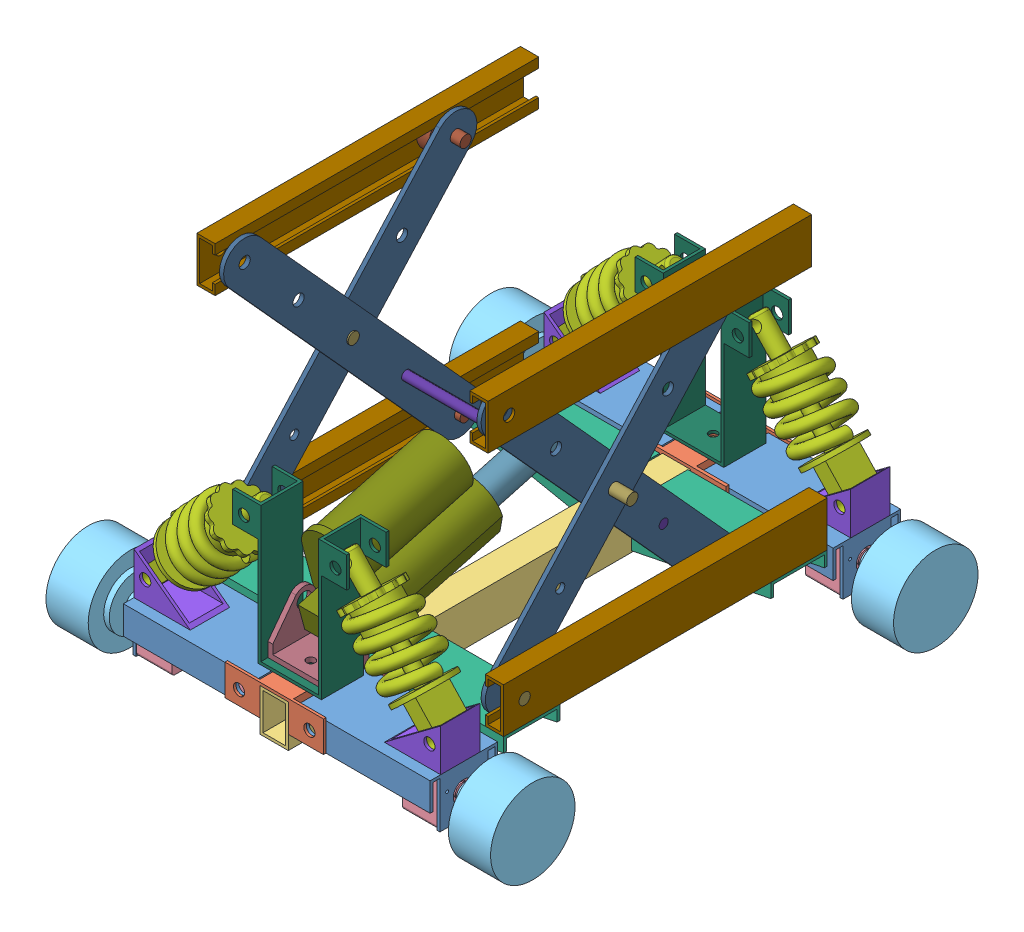
SolidWorks assembly 整体, configuration 默认. Lengths in mm.
Overall size (316 267.94 370.98).
48 component instances, 17 part files, 55 mates.
Components (placement in the parent):
- 电机安装板-1: 电机安装板 [默认] at (86.7266 -11.8451 70) size (94 35 48)
- 电机转动副-1: 电机转动副 [默认] at (82.9126 -31.7003 67.7925) size (70 22 52)
- 矩管-1: 矩管 [默认] at (70.1397 -10.4653 43.5249) x (0 0 -1) z (0 1 0) size (338 20 30)
- 电机和减速器-1: 电机和减速器 [默认] at (33.1161 1.0347 94) x (0 0 1) z (-1 0 0) size (33 33 95)
- 轮子加法兰-1: 轮子加法兰 [默认] at (-93.8839 -6.7848 84.7644) x (0 0.763194 -0.646169) z (1 0 0) size (60 60 47)
- 升降支撑板-1: 升降支撑板 [默认] at (17.4717 0.0393 25.7925) size (99 30 40)
- 减震器10cm中心距-1: 减震器10cm中心距 [默认] at (-6.3734 50.215 84.5) x (0.68369 0.729773 0) z (0 0 1) size (112 51.88 51.88)
- 减震器安装支架-1: 减震器安装支架 [默认] at (-18.6767 23.9575 82.5) size (40 30 28)
- 导轨-1: 导轨 [默认] at (-3.9885 11.2083 65.7925) x (-1 0 0) z (0 0 -1) size (13 32 230)
- 升降剪叉机构-1: 升降剪叉机构 [默认] at (-28.8839 73.8835 -86.4616) x (0 0.741103 0.671391) z (1 0 0) size (258 30 3)
- 轴承带丝杆-1: 轴承带丝杆 [默认] at (-42.8839 24.4917 -97.4559) x (0 -0.806832 -0.590781) z (1 0 0) size (28 28 21)
- 升降剪叉机构-3: 升降剪叉机构 [默认] at (-31.8839 55.9585 15.1833) x (0 0.741103 -0.671391) z (1 0 0) size (258 30 3)
- 轴承带丝杆-2: 轴承带丝杆 [默认] at (-42.8839 195.9799 -111.0939) x (0 0.187759 -0.982215) z (1 0 0) size (28 28 21)
- 减震器10cm中心距-2: 减震器10cm中心距 [默认] at (134.6055 50.215 108.5) x (-0.68369 0.729773 0) z (0 0 -1) size (112 51.88 51.88)
- 电机安装板-2: 电机安装板 [默认] at (41.5056 -11.8451 118) x (-1 0 0) z (0 0 -1) size (94 35 48)
- 减震器安装支架-2: 减震器安装支架 [默认] at (146.9089 23.9575 110.5) x (-1 0 0) z (0 0 -1) size (40 30 28)
- 轮子加法兰-2: 轮子加法兰 [默认] at (222.1161 -6.7848 84.7644) x (0 -0.763194 0.646169) z (-1 0 0) size (60 60 47)
- 电机和减速器-2: 电机和减速器 [默认] at (95.1161 1.0347 94) x (0 0 -1) z (1 0 0) size (33 33 95)
- 升降支撑板-2: 升降支撑板 [默认] at (110.7605 0.0393 65.7925) x (-1 0 0) z (0 0 -1) size (99 30 40)
- 升降剪叉机构-6: 升降剪叉机构 [默认] at (157.1161 55.9585 -66.6755) x (0 0.741103 0.671391) z (-1 0 0) size (258 30 3)
- 升降剪叉机构-7: 升降剪叉机构 [默认] at (160.1161 73.8835 34.9694) x (0 0.741103 -0.671391) z (-1 0 0) size (258 30 3)
- 轴承带丝杆-5: 轴承带丝杆 [默认] at (171.1161 35.5677 -89.3458) x (0 0.806832 0.590781) z (-1 0 0) size (28 28 21)
- 导轨-7: 导轨 [默认] at (132.2207 61.8611 65.7925) x (1 0 0) z (0 0 -1) size (13 32 230)
- 导轨-8: 导轨 [默认] at (-3.9885 180.1798 65.7925) x (-1 0 0) z (0 0 -1) size (13 32 230)
- 轮子加法兰-3: 轮子加法兰 [默认] at (-93.8839 -6.7848 -183.1793) x (0 -0.763194 -0.646169) z (1 0 0) size (60 60 47)
- 减震器10cm中心距-3: 减震器10cm中心距 [默认] at (-6.3734 50.215 -206.9149) x (0.68369 0.729773 0) z (0 0 1) size (112 51.88 51.88)
- 电机安装板-3: 电机安装板 [默认] at (86.7266 -11.8451 -216.4149) size (94 35 48)
- 电机和减速器-3: 电机和减速器 [默认] at (33.1161 1.0347 -192.4149) x (0 0 1) z (-1 0 0) size (33 33 95)
- 减震器安装支架-3: 减震器安装支架 [默认] at (-18.6767 23.9575 -208.9149) size (40 30 28)
- 电机安装板-4: 电机安装板 [默认] at (41.5056 -11.8451 -168.4149) x (-1 0 0) z (0 0 -1) size (94 35 48)
- 减震器10cm中心距-4: 减震器10cm中心距 [默认] at (134.6055 50.215 -182.9149) x (-0.68369 0.729773 0) z (0 0 -1) size (112 51.88 51.88)
- 减震器安装支架-4: 减震器安装支架 [默认] at (146.9089 23.9575 -180.9149) x (-1 0 0) z (0 0 -1) size (40 30 28)
- 电机和减速器-4: 电机和减速器 [默认] at (95.1161 1.0347 -192.4149) x (0 0 -1) z (1 0 0) size (33 33 95)
- 轮子加法兰-4: 轮子加法兰 [默认] at (222.1161 -6.7848 -183.1793) x (0 0.763194 0.646169) z (-1 0 0) size (60 60 47)
- 电机转动副-2: 电机转动副 [默认] at (45.3195 -31.7003 -166.2075) x (-1 0 0) z (0 0 -1) size (70 22 52)
- 升降支撑板-3: 升降支撑板 [默认] at (17.4717 0.0393 -164.2075) size (99 30 40)
- 升降支撑板-4: 升降支撑板 [默认] at (110.7605 0.0393 -124.2075) x (-1 0 0) z (0 0 -1) size (99 30 40)
- M820-1: M820 [默认] at (-24.8839 121.0204 -25.7461) x (0 0.001516 0.999999) z (-1 0 0) size (8 8 20)
- M820-2: M820 [默认] at (-24.8839 36.5347 50.7925) x (0 -0.186225 0.982507) z (-1 0 0) size (8 8 20)
- M820-3: M820 [默认] at (173.1161 36.5347 50.7925) x (0 -0.186225 0.982507) z (-1 0 0) size (8 8 20)
- M820-4: M820 [默认] at (173.1161 121.0204 -25.7461) x (0 0.001516 0.999999) z (-1 0 0) size (8 8 20)
- 推杆安装支架-1: 推杆安装支架 [默认] at (43.6161 55.5451 52.5195) x (0 0 -1) z (1 0 0) size (31 34.5 41)
- 推杆头-1: 推杆头 [默认] at (64.4401 54.9776 23.299) x (1 0 0) z (0 0.9648 0.262983) size (20 100 20)
- 减震器安装架-3: 减震器安装架 [默认] at (50.8491 12.0691 -177.2075) x (0 0 -1) z (1 0 0) size (30 98.12 81)
- 减震器安装架-4: 减震器安装架 [默认] at (77.383 12.0691 78.7925) x (0 0 1) z (-1 0 0) size (30 98.12 81)
- 105mm推杆-1: 105mm推杆 [默认] at (74.1161 88.7198 98.9982) x (0 0.262983 -0.9648) z (-1 0 0) size (114.5 80 40.32)
- 186推杆连接-1: 186推杆连接 [默认] at (-28.8839 66.5559 -75.859) x (0 0 -1) z (1 0 0) size (6.5 6.5 186)
- 导轨-14: 导轨 [默认] at (121.2207 230.8326 65.7925) x (1 0 0) z (0 0 -1) size (13 32 230)
Mates (geometry in assembly coordinates):
- 同心1: concentric: cylinder of 电机安装板-1 through (39.1161 9.5347 118) axis (0 0 -1) radius 4; cylinder of 电机转动副-1 through (39.1161 9.5347 119.7925) axis (0 0 -1) radius 4
- 重合1: coincident: plane of 电机安装板-1 through (86.7266 -11.8451 118) normal (0 0 1); plane of 电机转动副-1 through (52.1161 -22.4653 118) normal (0 0 -1)
- 同心2: concentric: cylinder of 电机转动副-1 through (64.1161 -22.4653 93.7925) axis (0 1 0) radius 4; cylinder of 矩管-1 through (64.1161 19.5347 93.7925) axis (0 -1 0) radius 4
- 重合2: coincident: plane of 电机转动副-1 through (54.1161 19.5347 119.7925) normal (0 -1 0); plane of 矩管-1 through (70.1397 19.5347 43.5249) normal (0 1 0)
- 同心3: concentric: cylinder of 电机安装板-1 through (-42.8839 1.0347 94) axis (-1 0 0) radius 7.5; cylinder of 电机和减速器-1 through (-43.8839 1.0347 94) axis (1 0 0) radius 5
- 重合3: coincident: plane of 电机安装板-1 through (-42.8839 -11.8451 70) normal (1 0 0); plane of 电机和减速器-1 through (-42.8839 15.5347 79.5) normal (-1 0 0)
- 重合4: coincident: plane of 电机和减速器-1 through (-61.8839 1.0347 94) normal (-1 0 0); plane of 轮子加法兰-1 through (-61.8839 1.0347 94) normal (1 0 0)
- 同心4: concentric: cylinder of 电机和减速器-1 through (-61.8839 1.0347 94) axis (1 0 0) radius 3; cylinder of 轮子加法兰-1 through (-61.8839 1.0347 94) axis (1 0 0) radius 3
- 重合9: coincident: circle of 矩管-1; cylinder of 升降支撑板-1 through (149.1161 4.5347 45.7925) axis (-1 0 0) radius 4
- 重合10: coincident: plane of 矩管-1 through (54.1161 19.5347 119.7925) normal (-1 0 0); plane of 升降支撑板-1 through (54.1161 20.5347 65.7925) normal (1 0 0)
- 重合11: coincident: plane of 电机和减速器-1 through (-42.8839 -13.4653 110.5) normal (0 0 1); plane of 减震器安装支架-1 through (-18.6767 23.9575 110.5) normal (0 0 1)
- 重合12: coincident: plane of 电机安装板-1 through (-44.8839 19.5347 118) normal (0 1 0); plane of 减震器安装支架-1 through (-44.8839 19.5347 110.5) normal (0 -1 0)
- 重合13: coincident: plane of 电机安装板-1 through (-44.8839 -0.4653 118) normal (-1 0 0); plane of 减震器安装支架-1 through (-44.8839 49.5347 110.5) normal (-1 0 0)
- 同心6: concentric: cylinder of 减震器10cm中心距-1 through (-36.8839 34.5347 108.5) axis (0 0 -1) radius 4; cylinder of 减震器安装支架-1 through (-36.8839 34.5347 110.5) axis (0 0 -1) radius 4
- 重合14: coincident: plane of 减震器10cm中心距-1 through (-36.8839 34.5347 108.5) normal (0 0 1); plane of 减震器安装支架-1 through (-42.8839 21.5347 108.5) normal (0 0 -1)
- 同心10: concentric: cylinder of 升降剪叉机构-1 through (-25.8839 36.5347 -172.5162) axis (-1 0 0) radius 4; cylinder of 轴承带丝杆-1 through (-21.8839 36.5347 -172.5162) axis (-1 0 0) radius 4
- 重合15: coincident: plane of 升降支撑板-1 through (-44.8839 20.5347 65.7925) normal (0 1 0); plane of 导轨-1 through (-31.8839 20.5347 -164.2075) normal (0 -1 0)
- 重合16: coincident: line of 升降支撑板-1 through (-44.8839 20.5347 25.7925) axis (0 -1 0); plane of 导轨-1 through (-44.8839 20.5347 -164.2075) normal (-1 0 0)
- 重合17: coincident: plane of 升降支撑板-1 through (17.4717 0.0393 65.7925) normal (0 0 1); plane of 导轨-1 through (-3.9885 11.2083 65.7925) normal (0 0 1)
- 相切1: tangent: plane of 导轨-1 through (-33.8839 50.5347 -164.2075) normal (0 -1 0); cylinder of 轴承带丝杆-1 through (-33.8839 36.5347 -172.5162) axis (-1 0 0) radius 14
- 重合20: coincident: circle of 升降剪叉机构-1; plane of 升降剪叉机构-3 through (-28.8839 36.5347 50.7925) normal (1 0 0)
- 重合21: coincident: plane of 导轨-1 through (-31.8839 50.5347 -164.2075) normal (1 0 0); plane of 升降剪叉机构-3 through (-31.8839 36.5347 50.7925) normal (-1 0 0)
- 同心12: concentric: cylinder of 升降剪叉机构-1 through (-25.8839 59.5413 -60.8618) axis (-1 0 0) radius 4; cylinder of 升降剪叉机构-3 through (-28.8839 59.5413 -60.8618) axis (-1 0 0) radius 4
- 同心13: concentric: cylinder of 升降剪叉机构-3 through (-28.8839 82.5479 -172.5162) axis (-1 0 0) radius 4; cylinder of 轴承带丝杆-2 through (-21.8839 82.5479 -172.5162) axis (-1 0 0) radius 4
- 重合33: coincident: plane of 升降支撑板-2 through (173.1161 20.5347 25.7925) normal (0 1 0); plane of 导轨-7 through (173.1161 20.5347 -164.2075) normal (0 -1 0)
- 同心17: concentric: cylinder of 升降剪叉机构-7 through (157.1161 36.5347 50.7925) axis (1 0 0) radius 4; cylinder of 导轨-7 through (161.1161 36.5347 50.7925) axis (1 0 0) radius 4
- 重合34: coincident: plane of 导轨-1 through (-3.9885 11.2083 65.7925) normal (0 0 1); line of 导轨-7 through (171.1161 22.5347 65.7925) axis (0 1 0)
- 重合35: coincident: plane of 升降支撑板-2 through (173.1161 20.5347 25.7925) normal (1 0 0); plane of 导轨-7 through (173.1161 52.5347 -164.2075) normal (1 0 0)
- 同心18: concentric: cylinder of 升降剪叉机构-1 through (-25.8839 82.5479 50.7925) axis (-1 0 0) radius 4; cylinder of 导轨-8 through (-32.8839 82.5479 50.7925) axis (-1 0 0) radius 4
- 重合36: coincident: plane of 导轨-1 through (-44.8839 20.5347 -164.2075) normal (-1 0 0); plane of 导轨-8 through (-44.8839 66.5479 -164.2075) normal (-1 0 0)
- 同心19: concentric: cylinder of 升降剪叉机构-1 through (-25.8839 59.5413 -60.8618) axis (-1 0 0) radius 4; cylinder of M820-1 through (-44.8839 59.5413 -60.8618) axis (1 0 0) radius 4
- 重合41: coincident: plane of 导轨-8 through (-44.8839 66.5479 -164.2075) normal (-1 0 0); plane of M820-1 through (-44.8839 59.5413 -60.8618) normal (-1 0 0)
- 重合43: coincident: plane of 导轨-1 through (-44.8839 20.5347 -164.2075) normal (-1 0 0); plane of M820-2 through (-44.8839 36.5347 50.7925) normal (-1 0 0)
- 同心21: concentric: cylinder of 导轨-1 through (-32.8839 36.5347 50.7925) axis (-1 0 0) radius 4; cylinder of M820-2 through (-44.8839 36.5347 50.7925) axis (1 0 0) radius 4
- 重合46: coincident: plane of 轴承带丝杆-5 through (171.1161 36.5347 -172.5162) normal (1 0 0); plane of 导轨-7 through (171.1161 22.5347 -164.2075) normal (-1 0 0)
- 重合47: coincident: plane of 导轨-1 through (-42.8839 50.5347 -164.2075) normal (1 0 0); plane of 轴承带丝杆-1 through (-42.8839 36.5347 -172.5162) normal (-1 0 0)
- 重合51: coincident: plane of 轴承带丝杆-2 through (-42.8839 82.5479 -172.5162) normal (-1 0 0); plane of 导轨-8 through (-42.8839 96.5479 -164.2075) normal (1 0 0)
- 重合57: coincident: plane of 矩管-1 through (74.1161 19.5347 119.7925) normal (1 0 0); plane of 电机转动副-2 through (74.1161 -0.4653 -218.2075) normal (-1 0 0)
- 平行1: parallel: plane of 电机安装板-4 through (173.1161 19.5347 -216.4149) normal (0 1 0); plane of 电机转动副-2 through (74.1161 21.5347 -218.2075) normal (0 1 0)
- 同心27: concentric: cylinder of 升降剪叉机构-1 through (-25.8839 48.038 -116.689) axis (-1 0 0) radius 3.25; cylinder of 推杆头-1 through (164.4401 48.038 -116.689) axis (-1 0 0) radius 3.25
- 重合61: coincident: plane of 导轨-1 through (-31.8839 20.5347 -164.2075) normal (0 -1 0); plane of 升降支撑板-3 through (-44.8839 20.5347 -124.2075) normal (0 1 0)
- 重合62: coincident: plane of 导轨-7 through (173.1161 20.5347 -164.2075) normal (0 -1 0); plane of 升降支撑板-4 through (173.1161 20.5347 -164.2075) normal (0 1 0)
- 重合63: coincident: plane of 电机转动副-2 through (74.1161 21.5347 -218.2075) normal (0 1 0); plane of 减震器安装架-3 through (41.6161 21.5347 -207.2075) normal (0 -1 0)
- 平行2: parallel: plane of 导轨-1 through (-44.8839 52.5347 -164.2075) normal (0 1 0); plane of 导轨-8 through (-31.8839 66.5479 -164.2075) normal (0 -1 0)
- 重合64: coincident: plane of 推杆安装支架-1 through (84.6161 23.5347 103.7925) normal (0 -1 0); plane of 减震器安装架-4 through (43.6161 23.5347 108.7925) normal (0 1 0)
- 重合65: coincident: plane of 推杆安装支架-1 through (84.6161 49.5347 81.2925) normal (1 0 0); plane of 减震器安装架-4 through (84.6161 23.5347 108.7925) normal (-1 0 0)
- 同心28: concentric: cylinder of 推杆安装支架-1 through (64.1161 -13.9653 93.7925) axis (0 1 0) radius 3; cylinder of 减震器安装架-4 through (64.1161 -70.5853 93.7925) axis (0 1 0) radius 3
- 同心29: concentric: cylinder of 矩管-1 through (64.1161 19.5347 93.7925) axis (0 -1 0) radius 4; cylinder of 推杆安装支架-1 through (64.1161 -13.9653 93.7925) axis (0 1 0) radius 3
- 同心30: concentric: cylinder of 推杆安装支架-1 through (84.6161 49.5347 81.2925) axis (-1 0 0) radius 5.25; cylinder of 105mm推杆-1 through (44.1161 49.5347 81.2925) axis (1 0 0) radius 4
- 同心31: concentric: cylinder of 推杆头-1 through (64.4401 48.4461 -126.1802) axis (0 -0.042957 0.999077) radius 10; cylinder of 105mm推杆-1 through (64.4401 41.9066 25.9137) axis (0 0.042957 -0.999077) radius 10
- 同心32: concentric: cylinder of 推杆头-1 through (164.4401 48.038 -116.689) axis (-1 0 0) radius 3.25; cylinder of 186推杆连接-1 through (157.1161 48.038 -116.689) axis (-1 0 0) radius 3.25
- 重合67: coincident: plane of 升降剪叉机构-1 through (-28.8839 36.5347 -172.5162) normal (-1 0 0); plane of 186推杆连接-1 through (-28.8839 48.038 -116.689) normal (-1 0 0)
- 同心33: concentric: cylinder of 升降剪叉机构-6 through (154.1161 82.5479 50.7925) axis (1 0 0) radius 4; cylinder of 导轨-14 through (150.1161 82.5479 50.7925) axis (1 0 0) radius 4
- 重合70: coincident: plane of 导轨-8 through (-44.8839 98.5479 -164.2075) normal (0 1 0); plane of 导轨-14 through (149.1161 98.5479 -164.2075) normal (0 1 0)
- 重合71: coincident: plane of 升降剪叉机构-7 through (160.1161 36.5347 50.7925) normal (1 0 0); plane of 导轨-14 through (160.1161 68.5479 -164.2075) normal (-1 0 0)
